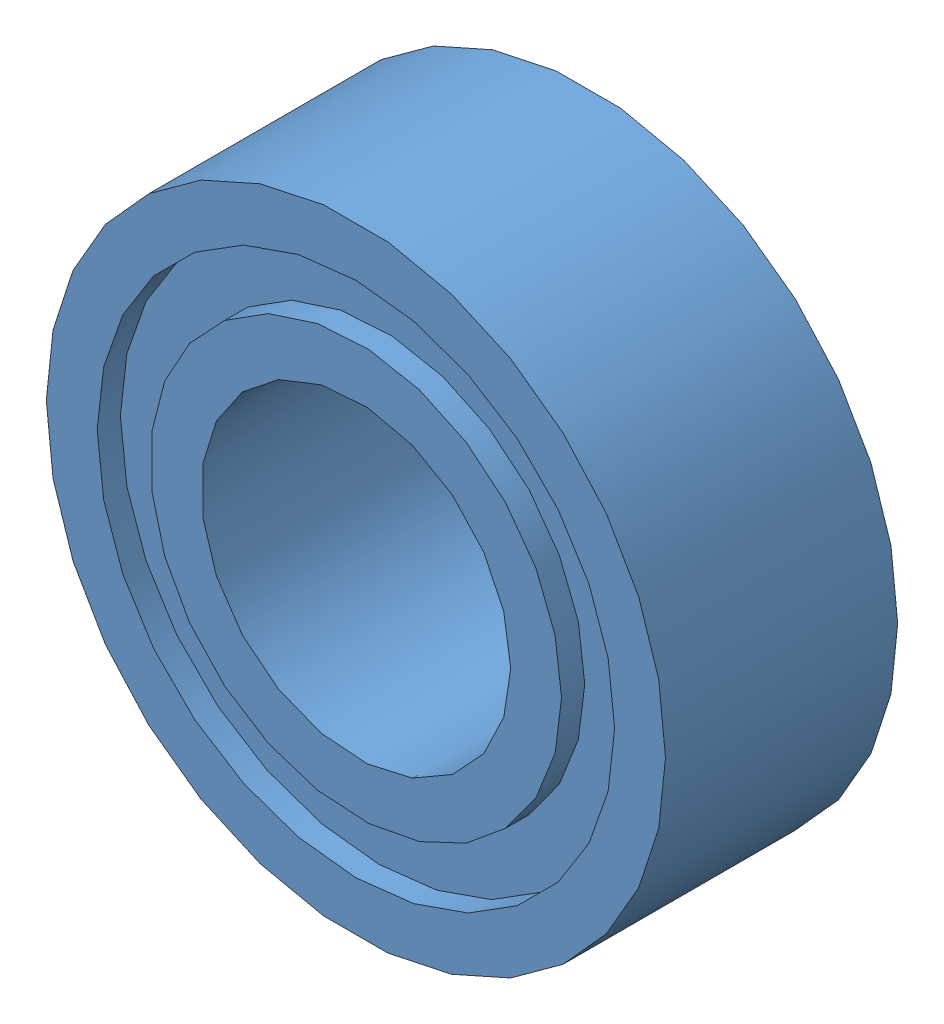
SolidWorks assembly Bearing_XX084 (MR84-ZZ ISB), configuration По умолчанию. Lengths in mm.
Overall size (8 8 3).
10 component instances, 2 part files, 1 mates.
Components (placement in the parent):
- Case_bearing_XX084 (MR84-ZZ ISB)-2: Case_bearing_XX084 (MR84-ZZ ISB) [По умолчанию] at origin size (8 8 3)
- Ball_bearing_XX084 (MR84-ZZ ISB)-2: Ball_bearing_XX084 (MR84-ZZ ISB) [По умолчанию] at (0.0407 2.9997 0) x (0.158188 -0.130413 -0.978759) z (-0.962811 0.1995 -0.182192) size (1.2 1.2 1.2)
- Ball_bearing_XX084 (MR84-ZZ ISB)-3: Ball_bearing_XX084 (MR84-ZZ ISB) [По умолчанию] at (-1.897 2.3241 0) x (0.205007 0.001779 -0.978759) z (-0.865792 -0.466058 -0.182192) size (1.2 1.2 1.2)
- Ball_bearing_XX084 (MR84-ZZ ISB)-4: Ball_bearing_XX084 (MR84-ZZ ISB) [По умолчанию] at (-2.9471 0.561 0) x (0.155901 0.133138 -0.978759) z (-0.363659 -0.913541 -0.182192) size (1.2 1.2 1.2)
- Ball_bearing_XX084 (MR84-ZZ ISB)-5: Ball_bearing_XX084 (MR84-ZZ ISB) [По умолчанию] at (-2.6182 -1.4646 0) x (0.033847 0.202201 -0.978759) z (0.308634 -0.933569 -0.182192) size (1.2 1.2 1.2)
- Ball_bearing_XX084 (MR84-ZZ ISB)-6: Ball_bearing_XX084 (MR84-ZZ ISB) [По умолчанию] at (-1.0642 -2.8049 0) x (-0.104044 0.176651 -0.978759) z (0.836514 -0.516769 -0.182192) size (1.2 1.2 1.2)
- Ball_bearing_XX084 (MR84-ZZ ISB)-7: Ball_bearing_XX084 (MR84-ZZ ISB) [По умолчанию] at (0.9877 -2.8327 0) x (-0.193252 0.068445 -0.978759) z (0.97298 0.141832 -0.182192) size (1.2 1.2 1.2)
- Ball_bearing_XX084 (MR84-ZZ ISB)-8: Ball_bearing_XX084 (MR84-ZZ ISB) [По умолчанию] at (2.5775 -1.5351 0) x (-0.192035 -0.071788 -0.978759) z (0.654178 0.734069 -0.182192) size (1.2 1.2 1.2)
- Ball_bearing_XX084 (MR84-ZZ ISB)-9: Ball_bearing_XX084 (MR84-ZZ ISB) [По умолчанию] at (2.9612 0.4808 0) x (-0.100963 -0.17843 -0.978759) z (0.029278 0.982827 -0.182192) size (1.2 1.2 1.2)
- Ball_bearing_XX084 (MR84-ZZ ISB)-10: Ball_bearing_XX084 (MR84-ZZ ISB) [По умолчанию] at (1.9594 2.2717 0) x (0.037351 -0.201583 -0.978759) z (-0.60932 0.771709 -0.182192) size (1.2 1.2 1.2)
Mates (geometry in assembly coordinates):
- Касательность1: tangent: torus of Case_bearing_XX084 (MR84-ZZ ISB)-2; sphere of Ball_bearing_XX084 (MR84-ZZ ISB)-2
